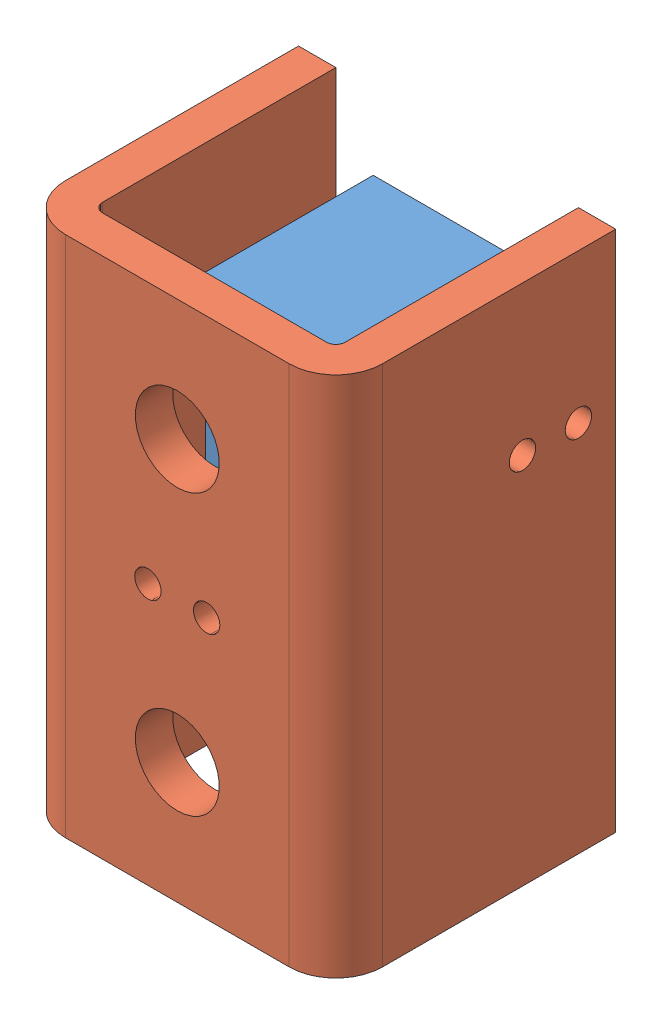
SolidWorks assembly Inital Thrust Setup, configuration Default. Lengths in mm.
Overall size (53.97 88.9 67.1).
4 component instances, 4 part files, 7 mates.
Components (placement in the parent):
- Testing Manifold-1: Testing Manifold [Default] at origin size (41.28 50.8 28.58)
- 33125T475_Strut Channel Bracket-1: 33125T475_Strut Channel Bracket [33125T475] at (-1.5875 25.4 26.9875) x (0 -1 0) z (0 0 1) size (88.9 53.98 47.62)
- C15_212EP10FF_000-1: C15_212EP10FF_000 [Default] at (-1.5875 25.4 4.572) x (0.730738 0.682658 0) z (0.682658 -0.730738 0) size (15 56.18 15)
- grainger-36x026-1: grainger-36x026 [Default] at (-1.5875 4.1631 7.9375) x (0 -1 0) z (0 0 1) size (18.47 12.77 12.72)
Mates (geometry in assembly coordinates):
- Coincident1: coincident anti-aligned: plane of Testing Manifold-1 through (19.05 50.8 -6.35) normal (1 0 0); plane of 33125T475_Strut Channel Bracket-1 through (19.05 69.85 47.625) normal (-1 0 0)
- Distance1: distance = 19.05 mm anti-aligned: plane of Testing Manifold-1 through (19.05 50.8 22.225) normal (0 0 1); plane of 33125T475_Strut Channel Bracket-1 through (-28.575 69.85 41.275) normal (0 0 -1)
- Concentric2: concentric aligned: cylinder of Testing Manifold-1 through (-1.5875 25.4 -0.715) axis (0 0 -1) radius 7.5311; cylinder of C15_212EP10FF_000-1 through (-1.5875 25.4 35.5139) axis (0 0 -1) radius 7.5
- Coincident2: coincident anti-aligned: plane of Testing Manifold-1 through (-1.5875 28.8163 4.572) normal (0 0 1); plane of C15_212EP10FF_000-1 through (1.0249 27.8405 4.572) normal (0 0 -1)
- Distance2: distance = 19.05 mm aligned: plane of Testing Manifold-1 through (0 50.8 0) normal (0 1 0); plane of 33125T475_Strut Channel Bracket-1 through (25.4 69.85 47.625) normal (0 1 0)
- Coincident4: coincident anti-aligned: line of Testing Manifold-1 through (-1.5875 0 7.9375) axis (0 1 0); line of grainger-36x026-1 through (-1.5875 4.1631 7.9375) axis (0 -1 0)
- Distance3: distance = 2.54 mm anti-aligned: plane of grainger-36x026-1 through (-1.5875 -2.54 7.9375) normal (0 1 0); plane of Testing Manifold-1 through (0 0 0) normal (0 -1 0)
